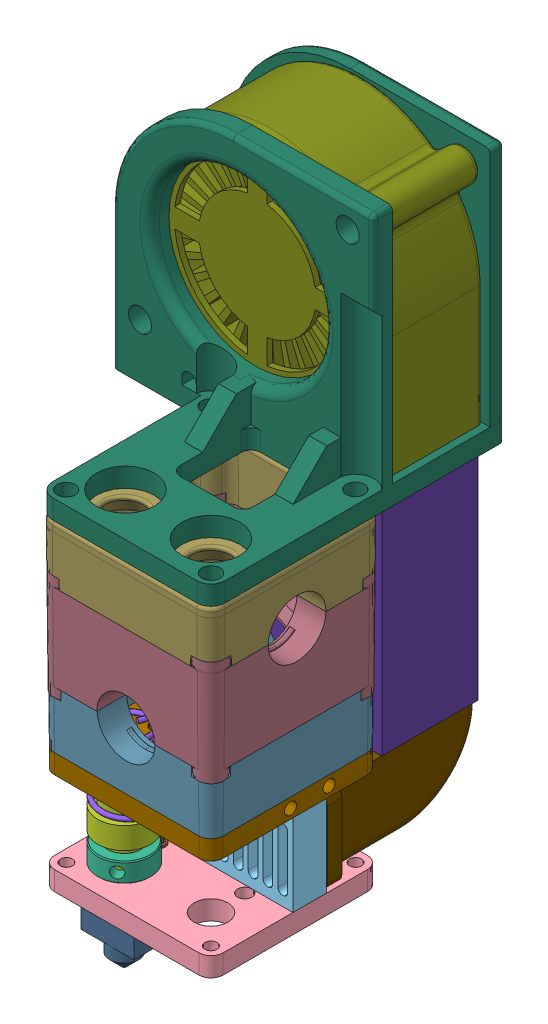
SolidWorks assembly Header Assembly, configuration Default. Lengths in mm.
Overall size (54.2 135.5 61.15).
56 component instances, 30 part files, 85 mates.
Components (placement in the parent):
- 1242-B2P-A-1: 1242-B2P-A [Default] at (15 166.7164 -15) x (0.653457 0 -0.756964) z (0.756964 0 0.653457) size (6 10 6) (hidden)
- 1074-Z1P-A (1)-1: 1074-Z1P-A (1) [Default] at (15 -2.1439 -15) x (-0.072213 0 0.997389) z (-0.997389 0 -0.072213) size (5.99 96 5.96) (hidden)
- 1065-Z1P-B-1: 1065-Z1P-B [Default] at (-72.0277 55 0) x (0 -0.954517 -0.298157) z (1 0 0) size (12 12 35) (hidden)
- 1348 Bolt M3x4-1: 1348 Bolt M3x4 [Default] at (-14 23 -7) x (0 0.977014 0.213175) z (0 -0.213175 0.977014) size (5.81 6.32 5.8) (hidden)
- 1353-Z1P-A-1: 1353-Z1P-A [Default] at (29.9776 18.5792 -12.331) x (0.018339 -0.024843 0.999523) z (-0.706869 0.706685 0.030534) size (4.33 17.6 4.33) (hidden)
- 1313-Z1P-A-1: 1313-Z1P-A [Default] at (-13.7632 9.3495 -2.0661) x (0 -0.006507 0.999979) z (-0.707107 -0.707092 -0.004601) size (30 10.3 30) (hidden)
  - Fan Base 30x30-1: Fan Base 30x30 [Default] at (1.9775 7.6443 16.6801) size (30 10.3 30)
  - Fan Rotor 30x30-1: Fan Rotor 30x30 [Default] at (1.9775 9.9443 16.6801) size (26.91 8.35 27.44)
- 1351 Bolt m2-1: 1351 Bolt m2 [Default] at (-10 2 -3.4) x (0.998549 0.053858 0) z (-0.053858 0.998549 0) size (4.5 11.64 4.5)
- 1200-Z1P-A ISO 7380 M3x8 new-1: 1200-Z1P-A ISO 7380 M3x8 new [Default] at (-13.5 8 -3) x (0.998424 0 0.056118) z (0.056118 0 -0.998424) size (5.48 9.75 5.45)
- 1200-Z1P-A ISO 7380 M3x8-1: 1200-Z1P-A ISO 7380 M3x8 [Default] at (-11.5 17 -3) x (0.998345 0 0.057515) z (-0.057515 0 0.998345) size (5.48 9.75 5.45)
- 1306-Z2P-B-1: 1306-Z2P-B [Default] at origin size (35 4 35)
- 1308-Z2P-B-1: 1308-Z2P-B [Default] at (10.0875 4 -0.1936) size (35 17 7)
- 1310-Z2P-A-1: 1310-Z2P-A [Default] at (-9 8.9059 9) x (-0.830792 0 0.556583) z (-0.556583 0 -0.830792) size (11 12 11)
- 1309-Z2P-B-1: 1309-Z2P-B [Default] at (-9 0.5 9) x (0.937816 0 0.347134) z (-0.347134 0 0.937816) size (11 18 11)
- 1311-Z2P-A-1: 1311-Z2P-A [Default] at (-9.1227 15.0714 9.0863) x (0.937816 0 0.347134) z (-0.347134 0 0.937816) size (10.73 18.5 10.7)
- 1307-Z2P-B-1: 1307-Z2P-B [Default] at (0 21 0) size (35 4 35)
- 1301-Z2P-D_simulation-1: 1301-Z2P-D_simulation [Default] at (-9 -9.5 9) x (-0.000143 0 -1) z (1 0 -0.000143) size (20 15 11)
- 1352-B2P-A Stelschroef M3x12-1: 1352-B2P-A Stelschroef M3x12 [Default] at (-9 -7.3103 2) size (3 11.75 3)
- 1330 Fan 25x25-1: 1330 Fan 25x25 [Default] at (16.6801 10.0225 1.1443) x (0 1 0) z (-1 0 0) size (25 6.9 25) (hidden)
  - 1330-Z1P-B Fan Base 25x25-1: 1330-Z1P-B Fan Base 25x25 [Default] at (1.9775 7.6443 16.6801) size (25 6.9 25) (hidden)
  - 1330 Fan Rotor 25x25-1: 1330 Fan Rotor 25x25 [Default] at (1.9775 10.5443 16.6801) size (22.24 4.21 22.61) (hidden)
- 1329-B2P-C-1: 1329-B2P-C [Default] at (0 -10.931 -17.7208) x (1 0 0) z (0 -0.006507 0.999979) size (82.24 36.5 38) (hidden)
- 1320-B2P-B-1: 1320-B2P-B [Default] at (0 55 0) size (35.89 12.45 35.89)
- 1321-B2P-B-1: 1321-B2P-B [Default] at (0 37 0) x (0 0 -1) z (1 0 0) size (35.71 22 35.71)
- 1322-B2P-C-1: 1322-B2P-C [Default] at (0 25 0) size (35.21 12.53 35.21)
- 1242-B2P-A-2: 1242-B2P-A [Default] at (-15 167.9604 -15) x (0.75201 0 -0.659151) z (0.659151 0 0.75201) size (6 10 6) (hidden)
- 1242-B2P-A-3: 1242-B2P-A [Default] at (-15 164.8514 15) x (0.99184 0 0.127492) z (-0.127492 0 0.99184) size (6 10 6) (hidden)
- 1242-B2P-A-4: 1242-B2P-A [Default] at (15 165.006 15) x (0.991764 0 0.12808) z (-0.12808 0 0.991764) size (6 10 6) (hidden)
- 1074-Z1P-A (1)-2: 1074-Z1P-A (1) [Default] at (15 -1.8684 15) x (-0.844227 0 -0.535986) z (0.535986 0 -0.844227) size (5.99 96 5.96) (hidden)
- 1074-Z1P-A (1)-3: 1074-Z1P-A (1) [Default] at (-15 112.3545 -15) x (0.802801 0 -0.596247) z (0.596247 0 0.802801) size (5.99 96 5.96) (hidden)
- 1074-Z1P-A (1)-4: 1074-Z1P-A (1) [Default] at (-15 -0.7419 15) x (0.947543 0 -0.319628) z (0.319628 0 0.947543) size (5.99 96 5.96) (hidden)
- 1065-Z1P-B-2: 1065-Z1P-B [Default] at (-8.8869 130.9971 20.3363) x (0.001683 -0.33781 -0.941213) z (0.999987 0.005193 -0.000076) size (12 12 35) (hidden)
- 1348 Bolt M3x4-2: 1348 Bolt M3x4 [Default] at (-14 22.9479 1) x (0 -0.528195 0.849123) z (0 -0.849123 -0.528195) size (5.81 6.32 5.8) (hidden)
- 1348 Bolt M3x4-3: 1348 Bolt M3x4 [Default] at (14 22.9479 1) x (0 -0.995996 -0.089397) z (0 -0.089397 0.995996) size (5.81 6.32 5.8) (hidden)
- 1348 Bolt M3x4-4: 1348 Bolt M3x4 [Default] at (14 23 -7) x (0 -0.992954 0.118502) z (0 0.118502 0.992954) size (5.81 6.32 5.8) (hidden)
- 1353-Z1P-A-2: 1353-Z1P-A [Default] at (46.9468 1.6084 -12.1372) x (-0.417565 0.412305 0.809719) z (-0.570648 0.574479 -0.5868) size (4.33 17.6 4.33) (hidden)
- 1353-Z1P-A-3: 1353-Z1P-A [Default] at (29.7625 18.6382 11.6679) x (0.018339 -0.024843 0.999523) z (-0.706869 0.706685 0.030534) size (4.33 17.6 4.33) (hidden)
- 1353-Z1P-A-4: 1353-Z1P-A [Default] at (46.7317 1.6674 11.8618) x (-0.417565 0.412305 0.809719) z (-0.570648 0.574479 -0.5868) size (4.33 17.6 4.33) (hidden)
- 1353-Z1P-A-5: 1353-Z1P-A [Default] at (-46.7317 1.6674 11.8618) x (-0.434049 -0.428903 -0.79224) z (0.558213 0.562195 -0.610193) size (4.33 17.6 4.33) (hidden)
- 1353-Z1P-A-6: 1353-Z1P-A [Default] at (-29.7611 18.7937 -12.0273) x (-0.434049 -0.428903 -0.79224) z (0.558213 0.562195 -0.610193) size (4.33 17.6 4.33) (hidden)
- 1353-Z1P-A-7: 1353-Z1P-A [Default] at (-46.7317 1.8235 -12.1377) x (-0.434049 -0.428903 -0.79224) z (0.558213 0.562195 -0.610193) size (4.33 17.6 4.33) (hidden)
- 1353-Z1P-A-8: 1353-Z1P-A [Default] at (-29.7611 18.6376 11.9722) x (-0.434049 -0.428903 -0.79224) z (0.558213 0.562195 -0.610193) size (4.33 17.6 4.33) (hidden)
- 1313-Z1P-A_2-1: 1313-Z1P-A_2 [Default] at (26.9148 -3.9223 16.3782) x (-0.70705 0.707117 -0.008076) z (0.008964 -0.002458 -0.999957) size (30 10.3 30) (hidden)
  - Fan Base 30x30-1: Fan Base 30x30 [Default] at (1.9775 7.6443 16.6801) size (30 10.3 30)
  - Fan Rotor 30x30-1: Fan Rotor 30x30 [Default] at (1.9775 9.9443 16.6801) size (26.91 8.35 27.44)
- 1351 Bolt m2-2: 1351 Bolt m2 [Default] at (10 2 -3.4) x (0.999819 0.019027 0) z (-0.019027 0.999819 0) size (4.5 11.64 4.5)
- 1200-Z1P-A ISO 7380 M3x8 new-2: 1200-Z1P-A ISO 7380 M3x8 new [Default] at (13.5 8 -3) x (-0.112729 0 0.993626) z (0.993626 0 0.112729) size (5.48 9.75 5.45)
- 1200-Z1P-A ISO 7380 M3x8-2: 1200-Z1P-A ISO 7380 M3x8 [Default] at (11.5 17 -3) x (0.91702 0 0.398841) z (-0.398841 0 0.91702) size (5.48 9.75 5.45)
- 1069-Z1P-A-1: 1069-Z1P-A [Default] at (-56.5764 86.2682 28.3082) x (-1 0 0) z (0 0 1) size (11.8 8.5 10) (hidden)
- 1071-Z1P-A-1: 1071-Z1P-A [Default] at (-66.8255 76.3721 21.6061) size (11.8 2.4 10.35) (hidden)
- hot-end-cooling-assembly-1: hot-end-cooling-assembly [Default] at (28.4389 88.0628 5.2626) x (0.999998 0 -0.001749) z (0 1 0) size (54.05 61.05 54)
  - fanduct-1: fanduct [Default] at (-7.4983 1.3043 -21.0628) size (54.05 61.05 54)
  - radialFan-50mm-1: radialFan-50mm [Default] at (-37.1059 25.4361 -0.1939) x (-1 0 0) z (0 1 0) size (50.1 50 20.19)
- duct-1: duct [Default] at (5.3981 21 -29.4152) x (-0.999998 0 0.001749) z (-0.001749 0 -0.999998) size (26 50 20)
- duct-turn-1: duct-turn [Default] at (-10.4777 -0.4093 -58.0032) x (-0.001749 0 -0.999998) z (0.999998 0 -0.001749) size (33.2 24 35)
Mates (geometry in assembly coordinates):
- Lock1: lock: unknown of 1306-Z2P-B-1
- Lock2: lock: unknown of 1309-Z2P-B-1; unknown of 1311-Z2P-A-1
- Concentric1: concentric anti-aligned: cylinder of 1309-Z2P-B-1 through (-9 15.7 9) axis (0 -1 0) radius 3.2; cylinder of 1310-Z2P-A-1 through (-9 63.9059 9) axis (0 1 0) radius 3.2
- Concentric2: concentric aligned: circle of 1301-Z2P-D_simulation-1; circle of 1352-B2P-A Stelschroef M3x12-1
- Distance1: distance = 7.9397 mm aligned: plane of 1352-B2P-A Stelschroef M3x12-1 through (-9 3.4397 2) normal (0 1 0); plane of 1301-Z2P-D_simulation-1 through (-15.0024 -4.5 -7.9991) normal (0 1 0)
- Concentric3: concentric aligned: circle of 1310-Z2P-A-1; cylinder of 1301-Z2P-D_simulation-1 through (-9 -4.5 9) axis (0 1 0) radius 2.6
- Concentric4: concentric aligned: cylinder of 1306-Z2P-B-1 through (-9 0 2) axis (0 -1 0) radius 1.5; cylinder of 1352-B2P-A Stelschroef M3x12-1 through (-9 4.4397 2) axis (0 -1 0) radius 1.5
- Concentric5: concentric anti-aligned: cylinder of 1306-Z2P-B-1 through (-9 0 9) axis (0 -1 0) radius 3.5; cylinder of 1310-Z2P-A-1 through (-9 63.9059 9) axis (0 1 0) radius 3.3
- Coincident5: coincident anti-aligned: plane of 1306-Z2P-B-1 through (0 4 0) normal (0 1 0); plane of 1310-Z2P-A-1 through (-11.9078 4 10.948) normal (0 -1 0)
- Coincident6: coincident anti-aligned: plane of 1309-Z2P-B-1 through (-7.4995 0.5 9.5554) normal (0 -1 0); plane of 1301-Z2P-D_simulation-1 through (-9 0.5 9) normal (0 1 0)
- Distance2: distance = 2 mm anti-aligned: plane of 1309-Z2P-B-1 through (-5.999 10 10.1108) normal (0 -1 0); plane of 1310-Z2P-A-1 through (-11.6585 8 10.7811) normal (0 1 0)
- Coincident8: coincident anti-aligned: plane of 1329-B2P-C-1 through (17.5 16.2966 17.4571) normal (0.707107 0.707092 0.004601); plane of 1313-Z1P-A_2-1/Fan Base 30x30-1 through (40.0216 -6.0294 -12.6805) normal (-0.707107 -0.707092 -0.004601)
- Concentric6: concentric aligned: cylinder of 1353-Z1P-A-3 through (20.5701 9.446 11.6081) axis (0.707107 0.707092 0.004601) radius 1.1; cylinder of 1313-Z1P-A_2-1/Fan Base 30x30-1 through (29.7625 18.6382 11.6679) axis (0.707107 0.707092 0.004601) radius 1.6
- Concentric7: concentric aligned: cylinder of 1353-Z1P-A-4 through (37.5393 -7.5248 11.8019) axis (0.707107 0.707092 0.004601) radius 1.1; circle of 1313-Z1P-A_2-1/Fan Base 30x30-1
- Concentric8: concentric aligned: cylinder of 1353-Z1P-A-2 through (37.7544 -7.5838 -12.197) axis (0.707107 0.707092 0.004601) radius 1.1; cylinder of 1313-Z1P-A_2-1/Fan Base 30x30-1 through (46.9468 1.6084 -12.1372) axis (0.707107 0.707092 0.004601) radius 1.6
- Concentric9: concentric aligned: cylinder of 1353-Z1P-A-1 through (20.7852 9.387 -12.3909) axis (0.707107 0.707092 0.004601) radius 1.1; circle of 1313-Z1P-A_2-1/Fan Base 30x30-1
- Coincident9: coincident anti-aligned: plane of 1353-Z1P-A-1 through (29.9776 18.5792 -12.331) normal (-0.707107 -0.707092 -0.004601); plane of 1313-Z1P-A_2-1/Fan Base 30x30-1 through (47.3048 1.2536 -12.6331) normal (0.707107 0.707092 0.004601)
- Coincident10: coincident anti-aligned: plane of 1353-Z1P-A-3 through (29.7625 18.6382 11.6679) normal (-0.707107 -0.707092 -0.004601); plane of 1313-Z1P-A_2-1/Fan Base 30x30-1 through (47.3048 1.2536 -12.6331) normal (0.707107 0.707092 0.004601)
- Coincident11: coincident anti-aligned: plane of 1353-Z1P-A-4 through (46.7317 1.6674 11.8618) normal (-0.707107 -0.707092 -0.004601); plane of 1313-Z1P-A_2-1/Fan Base 30x30-1 through (47.3048 1.2536 -12.6331) normal (0.707107 0.707092 0.004601)
- Coincident12: coincident anti-aligned: plane of 1353-Z1P-A-2 through (46.9468 1.6084 -12.1372) normal (-0.707107 -0.707092 -0.004601); plane of 1313-Z1P-A_2-1/Fan Base 30x30-1 through (47.3048 1.2536 -12.6331) normal (0.707107 0.707092 0.004601)
- Concentric10: concentric anti-aligned: circle of 1329-B2P-C-1; circle of 1353-Z1P-A-4
- Concentric11: concentric aligned: cylinder of 1313-Z1P-A-1/Fan Base 30x30-1 through (-29.7611 18.7937 -12.0273) axis (-0.707107 0.707092 0.004601) radius 1.6; cylinder of 1353-Z1P-A-6 through (-20.5687 9.6016 -12.0871) axis (-0.707107 0.707092 0.004601) radius 1.1
- Concentric12: concentric aligned: cylinder of 1313-Z1P-A-1/Fan Base 30x30-1 through (-29.7611 18.6376 11.9722) axis (-0.707107 0.707092 0.004601) radius 1.6; cylinder of 1353-Z1P-A-8 through (-20.5687 9.4454 11.9124) axis (-0.707107 0.707092 0.004601) radius 1.1
- Concentric13: concentric aligned: cylinder of 1313-Z1P-A-1/Fan Base 30x30-1 through (-46.7317 1.6674 11.8618) axis (-0.707107 0.707092 0.004601) radius 1.6; cylinder of 1353-Z1P-A-5 through (-37.5393 -7.5248 11.8019) axis (-0.707107 0.707092 0.004601) radius 1.1
- Concentric14: concentric aligned: cylinder of 1313-Z1P-A-1/Fan Base 30x30-1 through (-46.7317 1.8235 -12.1377) axis (-0.707107 0.707092 0.004601) radius 1.6; cylinder of 1353-Z1P-A-7 through (-37.5393 -7.3687 -12.1975) axis (-0.707107 0.707092 0.004601) radius 1.1
- Coincident14: coincident anti-aligned: plane of 1313-Z1P-A-1/Fan Base 30x30-1 through (-47.0852 1.4732 -12.64) normal (-0.707107 0.707092 0.004601); circle of 1353-Z1P-A-7
- Coincident15: coincident anti-aligned: plane of 1313-Z1P-A-1/Fan Base 30x30-1 through (-47.0852 1.4732 -12.64) normal (-0.707107 0.707092 0.004601); plane of 1353-Z1P-A-6 through (-29.7611 18.7937 -12.0273) normal (0.707107 -0.707092 -0.004601)
- Coincident16: coincident anti-aligned: plane of 1313-Z1P-A-1/Fan Base 30x30-1 through (-47.0852 1.4732 -12.64) normal (-0.707107 0.707092 0.004601); plane of 1353-Z1P-A-8 through (-29.7611 18.6376 11.9722) normal (0.707107 -0.707092 -0.004601)
- Coincident17: coincident anti-aligned: plane of 1313-Z1P-A-1/Fan Base 30x30-1 through (-47.0852 1.4732 -12.64) normal (-0.707107 0.707092 0.004601); plane of 1353-Z1P-A-5 through (-46.7317 1.6674 11.8618) normal (0.707107 -0.707092 -0.004601)
- Concentric15: concentric aligned: circle of 1329-B2P-C-1; cylinder of 1353-Z1P-A-7 through (-37.5393 -7.3687 -12.1975) axis (-0.707107 0.707092 0.004601) radius 1.1
- Concentric16: concentric aligned: circle of 1329-B2P-C-1; cylinder of 1353-Z1P-A-5 through (-37.5393 -7.5248 11.8019) axis (-0.707107 0.707092 0.004601) radius 1.1
- Coincident18: coincident anti-aligned: plane of 1313-Z1P-A-1/Fan Base 30x30-1 through (-39.802 -5.8098 -12.6874) normal (0.707107 -0.707092 -0.004601); plane of 1329-B2P-C-1 through (-17.5 16.2966 17.4571) normal (-0.707107 0.707092 0.004601)
- Concentric17: concentric anti-aligned: cylinder of 1306-Z2P-B-1 through (13.5 0 -3) axis (0 -1 0) radius 1.5; cylinder of 1200-Z1P-A ISO 7380 M3x8 new-2 through (13.5 0 -3) axis (0 1 0) radius 1.5
- Concentric18: concentric anti-aligned: cylinder of 1200-Z1P-A ISO 7380 M3x8 new-1 through (-13.5 0 -3) axis (0 1 0) radius 1.5; cylinder of 1306-Z2P-B-1 through (-13.5 0 -3) axis (0 -1 0) radius 1.5
- Coincident19: coincident anti-aligned: plane of 1200-Z1P-A ISO 7380 M3x8 new-1 through (-16.1957 0 -3.1515) normal (0 1 0); plane of 1306-Z2P-B-1 through (0 0 0) normal (0 -1 0)
- Coincident20: coincident anti-aligned: plane of 1306-Z2P-B-1 through (0 0 0) normal (0 -1 0); plane of 1200-Z1P-A ISO 7380 M3x8 new-2 through (13.8044 0 -5.6828) normal (0 1 0)
- Concentric19: concentric anti-aligned: cylinder of 1200-Z1P-A ISO 7380 M3x8 new-1 through (-13.5 0 -3) axis (0 1 0) radius 1.5; cylinder of 1308-Z2P-B-1 through (-13.5 4 -3) axis (0 -1 0) radius 1.25
- Concentric20: concentric anti-aligned: cylinder of 1308-Z2P-B-1 through (13.5 4 -3) axis (0 -1 0) radius 1.25; cylinder of 1200-Z1P-A ISO 7380 M3x8 new-2 through (13.5 0 -3) axis (0 1 0) radius 1.5
- Coincident21: coincident anti-aligned: plane of 1306-Z2P-B-1 through (0 4 0) normal (0 1 0); plane of 1308-Z2P-B-1 through (17.5 4 0.5) normal (0 -1 0)
- Concentric21: concentric aligned: cylinder of 1307-Z2P-B-1 through (11.5 21 -3) axis (0 -1 0) radius 1.5; cylinder of 1200-Z1P-A ISO 7380 M3x8-2 through (11.5 25 -3) axis (0 -1 0) radius 1.5
- Concentric22: concentric aligned: cylinder of 1200-Z1P-A ISO 7380 M3x8-1 through (-11.5 25 -3) axis (0 -1 0) radius 1.5; cylinder of 1307-Z2P-B-1 through (-11.5 21 -3) axis (0 -1 0) radius 1.5
- Coincident22: coincident anti-aligned: plane of 1200-Z1P-A ISO 7380 M3x8-1 through (-14.1955 25 -3.1553) normal (0 -1 0); plane of 1307-Z2P-B-1 through (0 25 0) normal (0 1 0)
- Coincident23: coincident anti-aligned: plane of 1307-Z2P-B-1 through (0 25 0) normal (0 1 0); plane of 1200-Z1P-A ISO 7380 M3x8-2 through (9.024 25 -4.0769) normal (0 -1 0)
- Concentric23: concentric anti-aligned: cylinder of 1308-Z2P-B-1 through (11.5 21 -3) axis (0 1 0) radius 1.25; cylinder of 1200-Z1P-A ISO 7380 M3x8-2 through (11.5 25 -3) axis (0 -1 0) radius 1.5
- Concentric24: concentric anti-aligned: cylinder of 1200-Z1P-A ISO 7380 M3x8-1 through (-11.5 25 -3) axis (0 -1 0) radius 1.5; cylinder of 1308-Z2P-B-1 through (-11.5 21 -3) axis (0 1 0) radius 1.25
- Coincident24: coincident anti-aligned: plane of 1308-Z2P-B-1 through (-17.5 21 0.5) normal (0 1 0); plane of 1307-Z2P-B-1 through (0 21 0) normal (0 -1 0)
- Concentric25: concentric anti-aligned: cylinder of 1307-Z2P-B-1 through (-17.5 22.9479 1) axis (-1 0 0) radius 1.25; cylinder of 1348 Bolt M3x4-2 through (-18 22.9479 1) axis (1 0 0) radius 1.5
- Concentric26: concentric aligned: cylinder of 1348 Bolt M3x4-1 through (-18 23 -7) axis (1 0 0) radius 1.5; cylinder of 1307-Z2P-B-1 through (17.5 23 -7) axis (1 0 0) radius 1.25
- Concentric27: concentric anti-aligned: cylinder of 1307-Z2P-B-1 through (17.5 23 -7) axis (1 0 0) radius 1.25; cylinder of 1348 Bolt M3x4-4 through (18 23 -7) axis (-1 0 0) radius 1.5
- Concentric33: concentric anti-aligned: cylinder of 1074-Z1P-A (1)-1 through (15 -1.6439 -15) axis (0 1 0) radius 1.5; cone of 1321-B2P-B-1 through (15 37 -15) axis (0 -1 0)
- Concentric34: concentric anti-aligned: cone of 1321-B2P-B-1 through (-15 37 -15) axis (0 -1 0); cylinder of 1074-Z1P-A (1)-3 through (-15 112.8545 -15) axis (0 1 0) radius 1.5
- Concentric35: concentric anti-aligned: cone of 1322-B2P-C-1 through (-15 25 -15) axis (0 -1 0); cylinder of 1074-Z1P-A (1)-3 through (-15 112.8545 -15) axis (0 1 0) radius 1.5
- Concentric36: concentric anti-aligned: cylinder of 1074-Z1P-A (1)-1 through (15 -1.6439 -15) axis (0 1 0) radius 1.5; cone of 1322-B2P-C-1 through (15 25 -15) axis (0 -1 0)
- Concentric37: concentric aligned: cylinder of 1065-Z1P-B-1 through (-54.5277 55 0) axis (-1 0 0) radius 6; cylinder of 1321-B2P-B-1 through (17.8571 55 0) axis (-1 0 0) radius 6
- Concentric39: concentric anti-aligned: cylinder of 1242-B2P-A-1 through (15 176.7164 -15) axis (0 -1 0) radius 1.6; cylinder of 1074-Z1P-A (1)-1 through (15 -1.6439 -15) axis (0 1 0) radius 1.5
- Concentric40: concentric anti-aligned: cylinder of 1242-B2P-A-4 through (15 175.006 15) axis (0 -1 0) radius 1.6; cylinder of 1074-Z1P-A (1)-2 through (15 68.1316 15) axis (0 1 0) radius 1.51
- Concentric41: concentric anti-aligned: cylinder of 1242-B2P-A-3 through (-15 174.8514 15) axis (0 -1 0) radius 1.6; cylinder of 1074-Z1P-A (1)-4 through (-15 69.2581 15) axis (0 1 0) radius 1.51
- Concentric42: concentric anti-aligned: cylinder of 1242-B2P-A-2 through (-15 177.9604 -15) axis (0 -1 0) radius 1.6; cylinder of 1074-Z1P-A (1)-3 through (-15 112.8545 -15) axis (0 1 0) radius 1.5
- Concentric44: concentric anti-aligned: cylinder of 1306-Z2P-B-1 through (15 0 15) axis (0 -1 0) radius 1.25; cylinder of 1074-Z1P-A (1)-2 through (15 -1.3684 15) axis (0 1 0) radius 1.5
- Concentric45: concentric anti-aligned: cylinder of 1306-Z2P-B-1 through (-15 0 15) axis (0 -1 0) radius 1.25; cylinder of 1074-Z1P-A (1)-4 through (-15 -0.2419 15) axis (0 1 0) radius 1.5
- Coincident29: coincident anti-aligned: plane of 1307-Z2P-B-1 through (17.5 25 -17.5) normal (1 0 0); plane of 1329-B2P-C-1 through (17.5 -1.1589 17.3435) normal (-1 0 0)
- Concentric47: concentric anti-aligned: cylinder of 1307-Z2P-B-1 through (17.5 22.9479 1) axis (1 0 0) radius 1.25; cylinder of 1348 Bolt M3x4-3 through (18 22.9479 1) axis (-1 0 0) radius 1.5
- Concentric48: concentric anti-aligned: cylinder of 1329-B2P-C-1 through (18 22.9479 1) axis (1 0 0) radius 1.55; cylinder of 1348 Bolt M3x4-3 through (18 22.9479 1) axis (-1 0 0) radius 1.5
- Concentric49: concentric anti-aligned: cylinder of 1329-B2P-C-1 through (18 23 -6.9998) axis (1 0 0) radius 1.55; cylinder of 1348 Bolt M3x4-4 through (18 23 -7) axis (-1 0 0) radius 1.5
- Coincident30: coincident anti-aligned: plane of 1329-B2P-C-1 through (18 -1.1589 17.3435) normal (1 0 0); plane of 1348 Bolt M3x4-3 through (18 24.4419 1.1341) normal (-1 0 0)
- Coincident31: coincident anti-aligned: plane of 1329-B2P-C-1 through (18 -1.1589 17.3435) normal (1 0 0); plane of 1348 Bolt M3x4-4 through (18 24.4894 -7.1778) normal (-1 0 0)
- Coincident32: coincident anti-aligned: plane of 1348 Bolt M3x4-1 through (-18 21.5345 -7.3198) normal (1 0 0); plane of 1329-B2P-C-1 through (-18 -1.1589 17.3435) normal (-1 0 0)
- Coincident33: coincident anti-aligned: plane of 1329-B2P-C-1 through (-18 -1.1589 17.3435) normal (-1 0 0); plane of 1348 Bolt M3x4-2 through (-18 23.7402 -0.2737) normal (1 0 0)
- Coincident35: coincident anti-aligned: plane of 1321-B2P-B-1 through (15 37 15) normal (0 -1 0); plane of 1322-B2P-C-1 through (17.6047 37 -12.4664) normal (0 1 0)
- Coincident36: coincident anti-aligned: plane of 1307-Z2P-B-1 through (0 25 0) normal (0 1 0); plane of 1322-B2P-C-1 through (-15 25 15) normal (0 -1 0)
- Concentric51: concentric aligned: cone of 1320-B2P-B-1 through (-15 67 -15) axis (0 1 0); cylinder of 1074-Z1P-A (1)-3 through (-15 112.8545 -15) axis (0 1 0) radius 1.5
- Concentric52: concentric aligned: cylinder of 1074-Z1P-A (1)-1 through (15 -1.6439 -15) axis (0 1 0) radius 1.5; cone of 1320-B2P-B-1 through (15 67 -15) axis (0 1 0)
- Coincident37: coincident anti-aligned: plane of 1320-B2P-B-1 through (-15.8571 55 -12.1832) normal (0 -1 0); plane of 1321-B2P-B-1 through (15 55 15) normal (0 1 0)
- Coincident38: coincident anti-aligned: circle of 1307-Z2P-B-1; cylinder of 1074-Z1P-A (1)-3 through (-15 112.8545 -15) axis (0 1 0) radius 1.5
- Coincident39: coincident anti-aligned: plane of 1320-B2P-B-1 through (-15 67 -15) normal (0 1 0); plane of hot-end-cooling-assembly-1/fanduct-1 through (14.9098 67 14.9102) normal (0 -1 0)
- Concentric53: concentric anti-aligned: cone of 1320-B2P-B-1 through (15 67 15) axis (0 1 0); cylinder of hot-end-cooling-assembly-1/fanduct-1 through (15 71 15) axis (0 -1 0) radius 1.875
- Parallel1: parallel anti-aligned: cone of 1320-B2P-B-1 through (-15 67 -15) axis (0 1 0); cylinder of hot-end-cooling-assembly-1/fanduct-1 through (-15.0624 71 -14.9575) axis (0 -1 0) radius 1.875
- Concentric56: concentric anti-aligned: cylinder of 1307-Z2P-B-1 through (-15 21 15) axis (0 -1 0) radius 1.5; cone of 1320-B2P-B-1 through (-15 67 15) axis (0 1 0)
- Parallel3: parallel anti-aligned: cone of 1320-B2P-B-1 through (-15 67 -15) axis (0 1 0); cylinder of hot-end-cooling-assembly-1/fanduct-1 through (-15.0624 71 -14.9575) axis (0 -1 0) radius 1.875
- Coincident40: coincident anti-aligned: plane of hot-end-cooling-assembly-1/fanduct-1 through (-10.4109 71 -19.8056) normal (-0.001749 0 -0.999998); plane of duct-1 through (15.5891 71 -19.8511) normal (0.001749 0 0.999998)
- Coincident41: coincident anti-aligned: plane of hot-end-cooling-assembly-1/fanduct-1 through (-10.4464 71 -40.1056) normal (0.999998 0 -0.001749); plane of duct-1 through (-10.4109 71 -19.8056) normal (-0.999998 0 0.001749)
- Coincident42: coincident aligned: plane of hot-end-cooling-assembly-1/fanduct-1 through (14.9098 71 14.9102) normal (0 1 0); plane of duct-1 through (5.3981 71 -29.4152) normal (0 1 0)
- Coincident48: coincident aligned: plane of duct-1 through (15.5891 71 -19.8511) normal (0.999998 0 -0.001749); plane of duct-turn-1 through (15.5821 21 -23.8511) normal (0.999998 0 -0.001749)
- Coincident49: coincident anti-aligned: plane of duct-1 through (5.3981 21 -29.4152) normal (0 -1 0); plane of duct-turn-1 through (-9.2109 21 -19.8077) normal (0 1 0)
- Coincident50: coincident aligned: line of duct-1 through (15.5541 21 -39.8511) axis (-0.999998 0 0.001749); line of duct-turn-1 through (13.5541 21 -39.8476) axis (-0.999998 0 0.001749)
